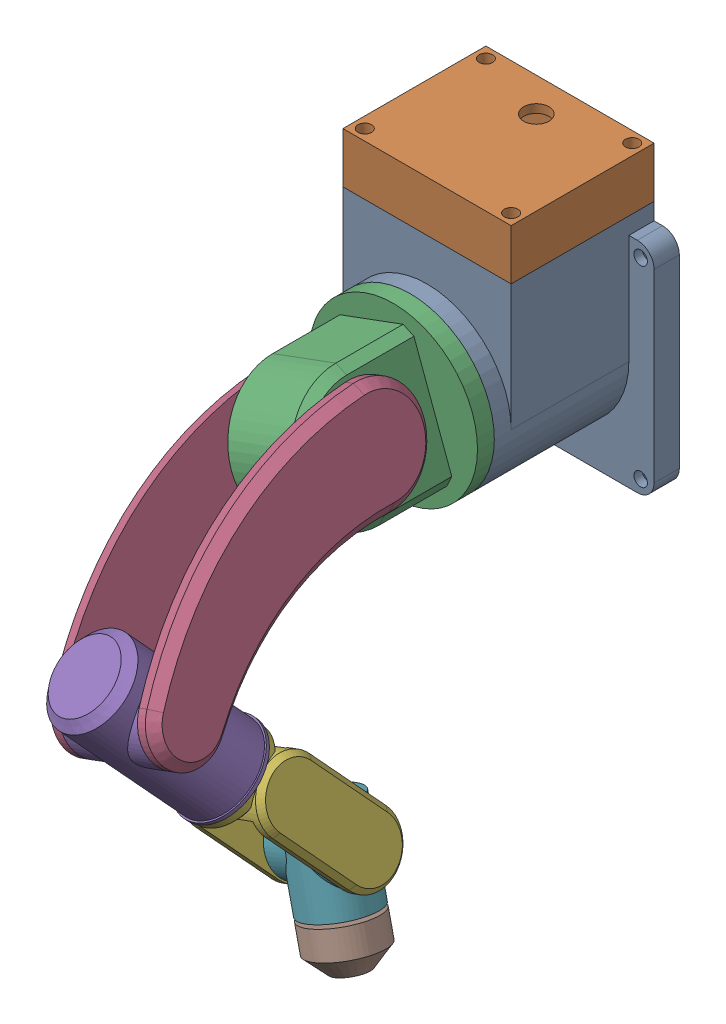
SolidWorks assembly Assem1, configuration Default. Lengths in mm.
Overall size (167.3 319.78 322.06).
8 component instances, 8 part files, 19 mates.
Components (placement in the parent):
- Part1-1: Part1 [Default] at (-273.4798 -166.0933 0) x (-1 0 0) z (0 1 0) size (130 95 145)
- Part2-1: Part2 [Default] at (-273.4798 -91.0933 42.5) x (-1 0 0) z (0 1 0) size (100 85 30)
- Part3-1: Part3 [Default] at (-273.4798 -166.0933 95) x (-0.938097 -0.346372 0) z (-0.346372 0.938097 0) size (100 87.5 100)
- Part4-1: Part4 [Default] at (-262.0408 -197.074 212.3376) x (0.310985 -0.842256 -0.440333) z (-0.938097 -0.346372 0) size (73.47 202.5 70)
- Part5-1: Part5 [Default] at (-259.9089 -202.848 302.103) x (0.938097 0.346372 0) z (0.265914 -0.720189 -0.640794) size (52 52 90)
- Part6-1: Part6 [Default] at (-233.3175 -274.8669 238.0235) x (0.938097 0.346372 0) z (-0.265914 0.720189 0.640794) size (55 50 90.82)
- Part7-1: Part7 [Default] at (-224.2483 -299.4295 197.3829) x (-0.938097 -0.346372 0) z (0.344283 -0.932441 0.109649) size (40 40 52)
- Part9-1: Part9 [Default] at (-206.3456 -347.9164 203.0846) x (0.668772 0.32553 0.668412) z (0.344283 -0.932441 0.109649) size (40 40 32)
Mates (geometry in assembly coordinates):
- Coincident1: coincident anti-aligned: plane of Part1-1 through (-231.4798 -86.0933 69.5) normal (1 0 0); plane of Part2-1 through (-231.4798 -66.0933 69.5) normal (-1 0 0)
- Coincident2: coincident anti-aligned: plane of Part1-1 through (-323.4798 -91.0933 0) normal (0 1 0); plane of Part2-1 through (-273.4798 -91.0933 42.5) normal (0 -1 0)
- Concentric1: concentric aligned: cylinder of Part1-1 through (-316.9798 -126.0933 78.5) axis (0 1 0) radius 2.5; cylinder of Part2-1 through (-316.9798 -111.0933 78.5) axis (0 1 0) radius 2.5
- Coincident3: coincident anti-aligned: plane of Part1-1 through (-273.4798 -166.0933 95) normal (0 0 1); plane of Part3-1 through (-273.4798 -166.0933 95) normal (0 0 -1)
- Coincident4: coincident aligned: circle of Part1-1; circle of Part3-1
- Coincident5: coincident anti-aligned: plane of Part3-1 through (-237.0384 -192.6127 185) normal (0.938097 0.346372 0); plane of Part4-1 through (-220.6307 -237.0506 140.3054) normal (-0.938097 -0.346372 0)
- Concentric2: concentric aligned: cylinder of Part3-1 through (-226.5749 -148.7747 145) axis (-0.938097 -0.346372 0) radius 25; cylinder of Part4-1 through (-268.7893 -164.3615 145) axis (-0.938097 -0.346372 0) radius 25
- Concentric3: concentric anti-aligned: cylinder of Part4-1 through (-245.9114 -226.3228 279.6752) axis (-0.938097 -0.346372 0) radius 20; cylinder of Part5-1 through (-274.0543 -236.7139 279.6752) axis (0.938097 0.346372 0) radius 20
- Coincident6: coincident anti-aligned: plane of Part4-1 through (-267.5355 -254.3692 140.3054) normal (0.938097 0.346372 0); plane of Part5-1 through (-274.0543 -236.7139 279.6752) normal (-0.938097 -0.346372 0)
- Coincident9: coincident anti-aligned: plane of Part5-1 through (-253.8802 -291.3525 263.6243) normal (0.265914 -0.720189 -0.640794); plane of Part6-1 through (-235.9766 -267.665 244.4315) normal (-0.265914 0.720189 0.640794)
- Coincident12: coincident anti-aligned: plane of Part5-1 through (-253.8802 -291.3525 263.6243) normal (0.265914 -0.720189 -0.640794); plane of Part6-1 through (-235.9766 -267.665 244.4315) normal (-0.265914 0.720189 0.640794)
- Concentric4: concentric anti-aligned: circle of Part5-1; circle of Part6-1
- Concentric5: concentric aligned: cylinder of Part6-1 through (-198.6007 -311.1508 199.5759) axis (-0.938097 -0.346372 0) radius 17.5; cylinder of Part7-1 through (-198.6007 -311.1508 199.5759) axis (-0.938097 -0.346372 0) radius 17.5
- Coincident13: coincident anti-aligned: plane of Part6-1 through (-218.6415 -372.3562 203.0353) normal (0.938097 0.346372 0); plane of Part7-1 through (-236.1246 -325.0057 199.5759) normal (-0.938097 -0.346372 0)
- Coincident14: coincident anti-aligned: plane of Part7-1 through (-208.7556 -341.3893 202.3171) normal (0.344283 -0.932441 0.109649); plane of Part9-1 through (-208.7556 -341.3893 202.3171) normal (-0.344283 0.932441 -0.109649)
- Concentric6: concentric aligned: cylinder of Part7-1 through (-208.7556 -341.3893 202.3171) axis (0.344283 -0.932441 0.109649) radius 7.5; cylinder of Part9-1 through (-208.7556 -341.3893 202.3171) axis (0.344283 -0.932441 0.109649) radius 7.5
- Paralelo2: parallel aligned: plane of Part4-1 through (-211.2497 -233.5869 140.3054) normal (0.938097 0.346372 0); plane of Part6-1 through (-204.8607 -272.5436 231.6156) normal (0.938097 0.346372 0)
- Bloquear5: lock: unknown of Part5-1; unknown of Part6-1
- Coincidente2: coincident anti-aligned: plane of Part1-1 through (-273.4798 -166.0933 0) normal (0 0 -1)
